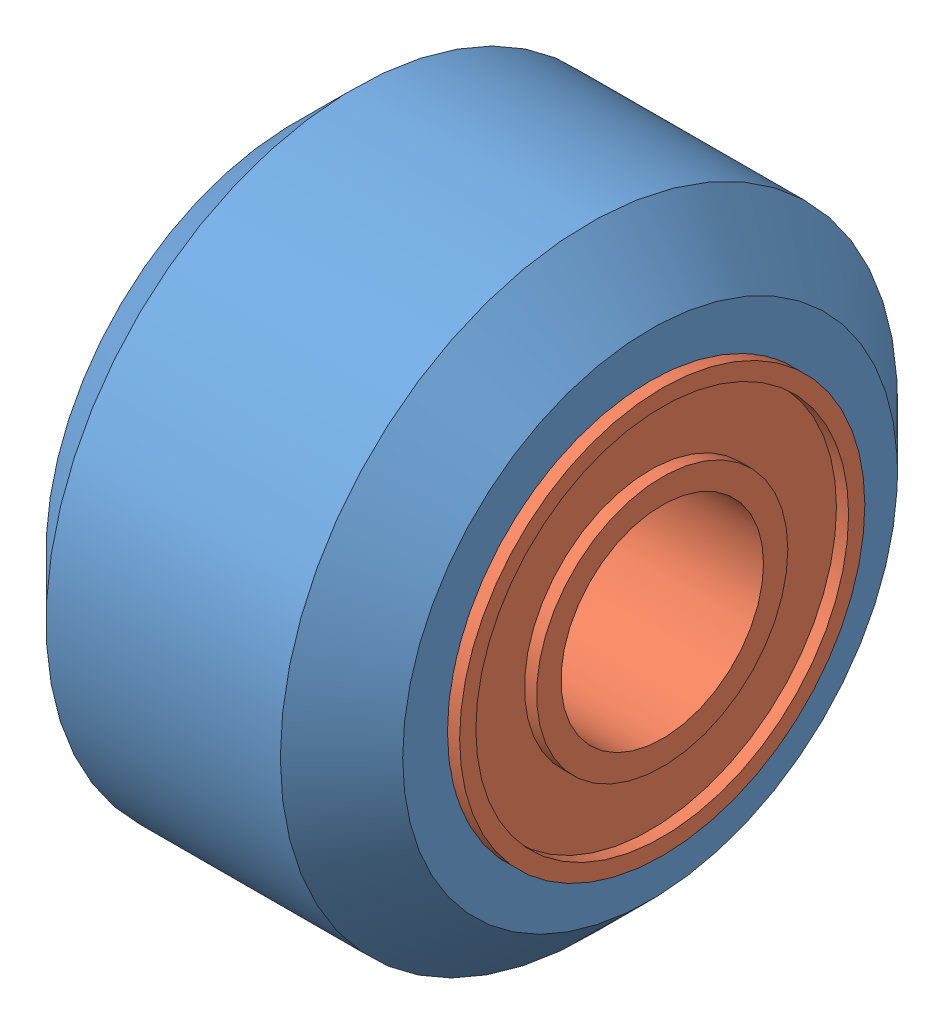
SolidWorks assembly Delrin Mini V Wheel Kit, configuration По умолчанию. Lengths in mm.
Overall size (9.4 15.23 15.23).
4 component instances, 3 part files, 3 mates.
Components (placement in the parent):
- Delrin Mini V Wheel-1: Delrin Mini V Wheel [Default] at origin size (8.8 15.23 15.23)
- Mini Ball Bearing 105zz 5x10x4-1: Mini Ball Bearing 105zz 5x10x4 [Default] at (2.6 0 0) size (4.2 10 10)
- Mini Ball Bearing 105zz 5x10x4-2: Mini Ball Bearing 105zz 5x10x4 [Default] at (-2.6 0 0) size (4.2 10 10)
- Mini V Wheel Precision Shim-2: Mini V Wheel Precision Shim [По умолчанию] at (-0.5 0 0) size (1 8 8)
Mates (geometry in assembly coordinates):
- Совпадение1: coincident aligned: circle of Delrin Mini V Wheel-1; circle of Mini Ball Bearing 105zz 5x10x4-2
- Совпадение3: coincident aligned: circle of Delrin Mini V Wheel-1; circle of Mini Ball Bearing 105zz 5x10x4-1
- Совпадение4: coincident aligned: circle of Mini Ball Bearing 105zz 5x10x4-1; circle of Mini V Wheel Precision Shim-2
